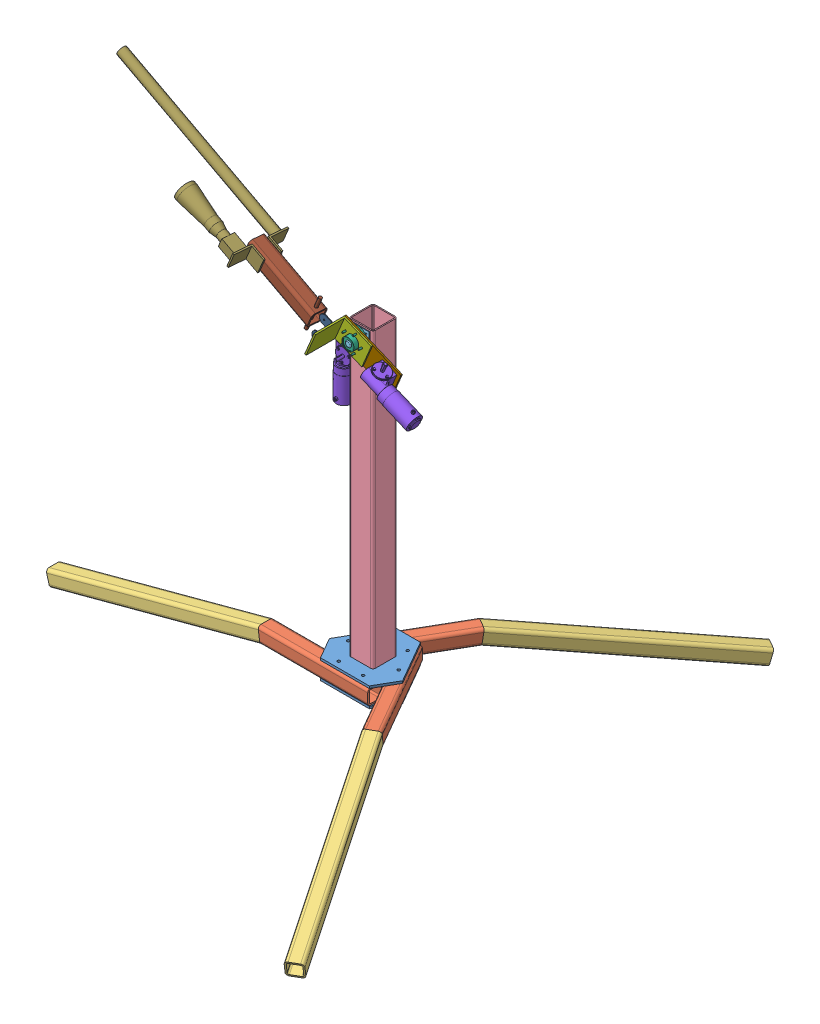
SolidWorks assembly Track Master, configuration Default. Lengths in mm.
Overall size (1965.36 1982.19 2177.49).
23 component instances, 12 part files, 49 mates.
Components (placement in the parent):
- Base Plate-1: Base Plate [Default] at origin size (304.8 9.53 263.96)
- Leg Assy-1: Leg Assy [Default] at (143.103 -48.9899 64.0264) x (0.866025 0 -0.5) z (0.5 0 0.866025) size (63.5 298 1340.44)
  - leg pt 1-1: leg pt 1 [Default] at (0 12.4774 0) size (63.5 63.5 457.2)
  - leg pt 2-1: leg pt 2 [Default] at (0 -104.7728 662.0038) x (1 0 0) z (0 -0.258819 0.965926) size (63.5 63.5 914.4)
- Leg Assy-2: Leg Assy [Default] at (-127 -48.9899 91.9176) x (0 0 1) z (-1 0 0) size (63.5 298 1340.44)
  - leg pt 1-1: leg pt 1 [Default] at (0 12.4774 0) size (63.5 63.5 457.2)
  - leg pt 2-1: leg pt 2 [Default] at (0 -104.7728 662.0038) x (1 0 0) z (0 -0.258819 0.965926) size (63.5 63.5 914.4)
- Leg Assy-3: Leg Assy [Default] at (-16.103 -48.9899 -155.944) x (-0.866025 0 -0.5) z (0.5 0 -0.866025) size (63.5 298 1340.44)
  - leg pt 1-1: leg pt 1 [Default] at (0 12.4774 0) size (63.5 63.5 457.2)
  - leg pt 2-1: leg pt 2 [Default] at (0 -104.7728 662.0038) x (1 0 0) z (0 -0.258819 0.965926) size (63.5 63.5 914.4)
- Base Plate-2: Base Plate [Default] at (0 -73.025 0) size (304.8 9.53 263.96)
- Post-1: Post [Default] at (0 614.3625 0) size (101.6 1219.2 101.6)
- Spindle-1: Spindle [Default] at (0 1179.5125 52.3875) x (0 0 1) z (-1 0 0) size (53.97 76.2 76.2)
- hub-1: hub [Default] at (0 1179.5125 53.975) x (0 0 1) z (-0.922004 0.387181 0) size (50.8 101.6 101.6)
- Upper angled plate-1: Upper angled plate [Default] at (0 1179.5125 79.375) x (0 0 1) z (-0.922004 0.387181 0) size (127 101.6 127)
- 59825K330-2: 59825K330 [59825K33] at (-109.22 1004.7605 12.0904) x (0 1 0) z (0 0 1) size (223.44 90.17 100.08)
- 59825K330-3: 59825K330 [59825K33] at (194.9009 1114.2236 137.795) x (-0.922004 0.387181 0) z (0.387181 0.922004 0) size (223.44 90.17 100.08)
- mid plate-1: mid plate [Default] at (58.5472 1154.9265 76.2) x (0 0 1) z (-0.922004 0.387181 0) size (6.35 101.6 254)
- ear-1: ear [Default] at (-74.5281 1166.0428 136.525) x (0 0 1) z (-0.922004 0.387181 0) size (3.17 38.1 44.45)
- ear-2: ear [Default] at (-42.5663 1242.1542 136.525) x (0 0 1) z (-0.922004 0.387181 0) size (3.17 38.1 44.45)
- Arm-1: Arm [Default] at (-96.5602 1243.6956 135.9124) x (-0.060226 0.025291 0.997864) z (-0.920035 0.386354 -0.065321) size (63.5 152.4 304.8)
- ant and cam-1: ant and cam [Ant] at (-334.179 1343.4799 87.224) x (-0.060226 0.025291 0.997864) z (-0.920035 0.386354 -0.065321) size (76.2 63.5 825.5)
- ant and cam-2: ant and cam [Cam] at (-338.0033 1345.0859 150.5884) x (0.060226 -0.025291 -0.997864) z (-0.920035 0.386354 -0.065321) size (76.2 76.2 330.2)
Mates (geometry in assembly coordinates):
- Coincident1: coincident aligned: plane of Base Plate-1 through (0 0 0) normal (0 0 1); plane of assembly through (0 0 0) normal (0 0 1)
- Coincident2: coincident aligned: plane of Base Plate-1 through (0 0 0) normal (1 0 0); plane of assembly through (0 0 0) normal (1 0 0)
- Coincident3: coincident aligned: plane of Base Plate-1 through (0 0 0) normal (0 1 0); plane of assembly through (0 0 0) normal (0 1 0)
- Coincident4: coincident anti-aligned: plane of Base Plate-1 through (-50.8 -4.7625 -146.647) normal (0 -1 0); plane of Leg Assy-1/leg pt 1-1 through (257.403 -4.7625 261.9998) normal (0 1 0)
- Coincident5: coincident anti-aligned: plane of Base Plate-1 through (-50.8 -4.7625 -146.647) normal (0 -1 0); plane of Leg Assy-2/leg pt 1-1 through (-355.6 -4.7625 91.9176) normal (0 1 0)
- Coincident6: coincident anti-aligned: plane of Base Plate-1 through (-50.8 -4.7625 -146.647) normal (0 -1 0); plane of Leg Assy-3/leg pt 1-1 through (98.197 -4.7625 -353.9174) normal (0 1 0)
- Concentric1: concentric aligned: cylinder of Base Plate-1 through (54.203 -4.7625 -89.9529) axis (0 1 0) radius 5.5563; cylinder of Leg Assy-1/leg pt 1-1 through (54.203 -68.2625 -89.9529) axis (0 1 0) radius 5.5563
- Concentric2: concentric aligned: cylinder of Base Plate-1 through (105.003 -4.7625 -1.9647) axis (0 1 0) radius 5.5563; cylinder of Leg Assy-1/leg pt 1-1 through (105.003 -68.2625 -1.9647) axis (0 1 0) radius 5.5563
- Concentric3: concentric aligned: cylinder of Base Plate-1 through (50.8 -4.7625 91.9176) axis (0 1 0) radius 5.5563; cylinder of Leg Assy-2/leg pt 1-1 through (50.8 -68.2625 91.9176) axis (0 1 0) radius 5.5563
- Concentric4: concentric aligned: cylinder of Base Plate-1 through (-50.8 -4.7625 91.9176) axis (0 1 0) radius 5.5563; cylinder of Leg Assy-2/leg pt 1-1 through (-50.8 -68.2625 91.9176) axis (0 1 0) radius 5.5563
- Concentric5: concentric aligned: cylinder of Base Plate-1 through (-105.003 -4.7625 -1.9647) axis (0 1 0) radius 5.5563; cylinder of Leg Assy-3/leg pt 1-1 through (-105.003 -68.2625 -1.9647) axis (0 1 0) radius 5.5563
- Concentric6: concentric aligned: cylinder of Base Plate-1 through (-54.203 -4.7625 -89.9529) axis (0 1 0) radius 5.5563; cylinder of Leg Assy-3/leg pt 1-1 through (-54.203 -68.2625 -89.9529) axis (0 1 0) radius 5.5563
- Coincident7: coincident anti-aligned: plane of Leg Assy-3/leg pt 1-1 through (98.197 -68.2625 -353.9174) normal (0 -1 0); plane of Base Plate-2 through (-50.8 -68.2625 -146.647) normal (0 1 0)
- Coincident8: coincident aligned: plane of Base Plate-1 through (0 0 0) normal (0 0 1); plane of Base Plate-2 through (0 -73.025 0) normal (0 0 1)
- Coincident9: coincident aligned: plane of Base Plate-1 through (0 0 0) normal (1 0 0); plane of Base Plate-2 through (0 -73.025 0) normal (1 0 0)
- Coincident10: coincident anti-aligned: plane of Base Plate-1 through (-50.8 4.7625 -146.647) normal (0 1 0); plane of Post-1 through (41.275 4.7625 -41.275) normal (0 -1 0)
- Coincident11: coincident aligned: plane of Post-1 through (0 614.3625 0) normal (0 0 1); plane of assembly through (0 0 0) normal (0 0 1)
- Coincident12: coincident aligned: plane of Post-1 through (0 614.3625 0) normal (1 0 0); plane of assembly through (0 0 0) normal (1 0 0)
- Coincident13: coincident anti-aligned: plane of Post-1 through (-41.275 1223.9625 50.8) normal (0 0 1); plane of Spindle-1 through (38.1 1217.6125 50.8) normal (0 0 -1)
- Coincident14: coincident anti-aligned: plane of Post-1 through (0 614.3625 0) normal (1 0 0); plane of Spindle-1 through (0 1179.5125 52.3875) normal (-1 0 0)
- Distance1: distance = 6.35 mm aligned: plane of Spindle-1 through (-38.1 1217.6125 53.975) normal (0 1 0); plane of Post-1 through (41.275 1223.9625 -41.275) normal (0 1 0)
- Concentric7: concentric aligned: cylinder of Spindle-1 through (0 1179.5125 53.975) axis (0 0 -1) radius 12.7; cylinder of hub-1 through (0 1179.5125 53.975) axis (0 0 -1) radius 12.7
- Coincident15: coincident anti-aligned: plane of Spindle-1 through (38.1 1217.6125 53.975) normal (0 0 1); circle of hub-1
- Distance4: distance = 6.35 mm anti-aligned: plane of hub-1 through (-19.6688 1132.6747 73.025) normal (0 0 1); plane of Upper angled plate-1 through (-38.8784 1250.9363 79.375) normal (0 0 -1)
- Concentric8: concentric aligned: cylinder of hub-1 through (0 1179.5125 53.975) axis (0 0 -1) radius 25.4; cylinder of Upper angled plate-1 through (0 1179.5125 206.375) axis (0 0 -1) radius 26.1937
- Coincident17: coincident aligned: plane of hub-1 through (0 1179.5125 53.975) normal (-0.922004 0.387181 0); plane of Upper angled plate-1 through (0 1179.5125 79.375) normal (-0.922004 0.387181 0)
- Coincident23: coincident anti-aligned: plane of hub-1 through (-19.6688 1132.6747 73.025) normal (0 0 1); plane of mid plate-1 through (155.9729 1058.9167 73.025) normal (0 0 -1)
- Concentric11: concentric aligned: cylinder of hub-1 through (0 1179.5125 53.975) axis (0 0 -1) radius 25.4; cylinder of mid plate-1 through (0 1179.5125 79.375) axis (0 0 -1) radius 25.4
- Parallel1: parallel aligned: plane of Upper angled plate-1 through (78.216 1201.7643 79.375) normal (0.387181 0.922004 0); plane of mid plate-1 through (-38.8784 1250.9363 79.375) normal (0.387181 0.922004 0)
- Coincident25: coincident anti-aligned: plane of Post-1 through (-50.8 1223.9625 41.275) normal (-1 0 0); plane of 59825K330-2 through (-50.8 1096.9625 34.925) normal (1 0 0)
- Distance5: distance = 15.875 mm aligned: plane of 59825K330-2 through (-188.694 1096.9625 34.925) normal (0 0 1); plane of Post-1 through (-41.275 1223.9625 50.8) normal (0 0 1)
- Distance6: distance = 127 mm aligned: plane of 59825K330-2 through (-132.08 1096.9625 12.0904) normal (0 1 0); plane of Post-1 through (41.275 1223.9625 -41.275) normal (0 1 0)
- Coincident28: coincident anti-aligned: plane of 59825K330-3 through (118.7315 1170.9761 79.375) normal (0 0 -1); plane of mid plate-1 through (155.9729 1058.9167 79.375) normal (0 0 1)
- Distance7: distance = 12.7 mm aligned: plane of 59825K330-3 through (118.7315 1170.9761 217.269) normal (0.387181 0.922004 0); plane of mid plate-1 through (-38.8784 1250.9363 79.375) normal (0.387181 0.922004 0)
- Distance8: distance = 12.7 mm aligned: plane of 59825K330-3 through (178.6838 1145.8 217.269) normal (0.922004 -0.387181 0); plane of mid plate-1 through (195.3105 1152.5923 79.375) normal (0.922004 -0.387181 0)
- Coincident31: coincident: plane of Upper angled plate-1 through (-38.8784 1250.9363 187.325) normal (-0.922004 0.387181 0); plane of ear-2 through (-41.337 1245.0816 161.925) normal (0.922004 -0.387181 0)
- Coincident32: coincident: plane of Upper angled plate-1 through (-38.8784 1250.9363 187.325) normal (-0.922004 0.387181 0); plane of ear-1 through (-73.2988 1168.9702 161.925) normal (0.922004 -0.387181 0)
- Distance9: distance = 76.2 mm: plane of ear-1 through (-108.4272 1183.7218 136.525) normal (0.387181 0.922004 0); plane of ear-2 through (-78.924 1253.9785 136.525) normal (-0.387181 -0.922004 0)
- Coincident34: coincident: plane of ear-1 through (-108.4272 1183.7218 161.925) normal (0 0 1); plane of ear-2 through (-76.4654 1259.8332 161.925) normal (0 0 1)
- Distance10: distance = 6.35 mm: plane of Upper angled plate-1 through (78.216 1201.7643 85.725) normal (0.387181 0.922004 0); plane of ear-2 through (-76.4654 1259.8332 136.525) normal (0.387181 0.922004 0)
- Distance11: distance = 25.4 mm: plane of Upper angled plate-1 through (-33.0237 1248.4777 187.325) normal (0 0 1); plane of ear-2 through (-76.4654 1259.8332 161.925) normal (0 0 1)
- Concentric12: concentric: cylinder of ear-2 through (-76.4654 1259.8332 136.525) axis (-0.387181 -0.922004 0) radius 9.525; cylinder of Arm-1 through (-64.1724 1289.1068 136.525) axis (-0.387181 -0.922004 0) radius 6.35
- Distance12: distance = 6.35 mm: plane of Arm-1 through (-344.2824 1358.5245 117.8597) normal (0.387181 0.922004 0); plane of ear-2 through (-78.924 1253.9785 136.525) normal (-0.387181 -0.922004 0)
- Coincident39: coincident anti-aligned: plane of Arm-1 through (-405.9982 1297.727 147.6849) normal (-0.060226 0.025291 0.997864); plane of ant and cam-2 through (-321.0852 1303.5455 152.6623) normal (0.060226 -0.025291 -0.997864)
- Coincident40: coincident aligned: plane of Arm-1 through (-364.6937 1390.73 116.0027) normal (0.387181 0.922004 0); plane of ant and cam-2 through (-296.4992 1362.0928 152.6623) normal (0.387181 0.922004 0)
- Distance13: distance = 76.2 mm anti-aligned: plane of ant and cam-2 through (-321.4677 1303.7061 158.9988) normal (0.920035 -0.386354 0.065321); plane of Arm-1 through (-404.086 1296.924 116.0027) normal (-0.920035 0.386354 -0.065321)
- Coincident42: coincident anti-aligned: plane of Arm-1 through (-402.1739 1296.121 84.3205) normal (0.060226 -0.025291 -0.997864); plane of ant and cam-1 through (-292.6749 1360.4868 89.298) normal (-0.060226 0.025291 0.997864)
- Coincident43: coincident aligned: plane of Arm-1 through (-364.6937 1390.73 116.0027) normal (0.387181 0.922004 0); plane of ant and cam-1 through (-292.6749 1360.4868 89.298) normal (0.387181 0.922004 0)
- Coincident44: coincident aligned: plane of ant and cam-1 through (-292.2924 1360.3262 82.9615) normal (0.920035 -0.386354 0.065321); plane of ant and cam-2 through (-321.4677 1303.7061 158.9988) normal (0.920035 -0.386354 0.065321)
